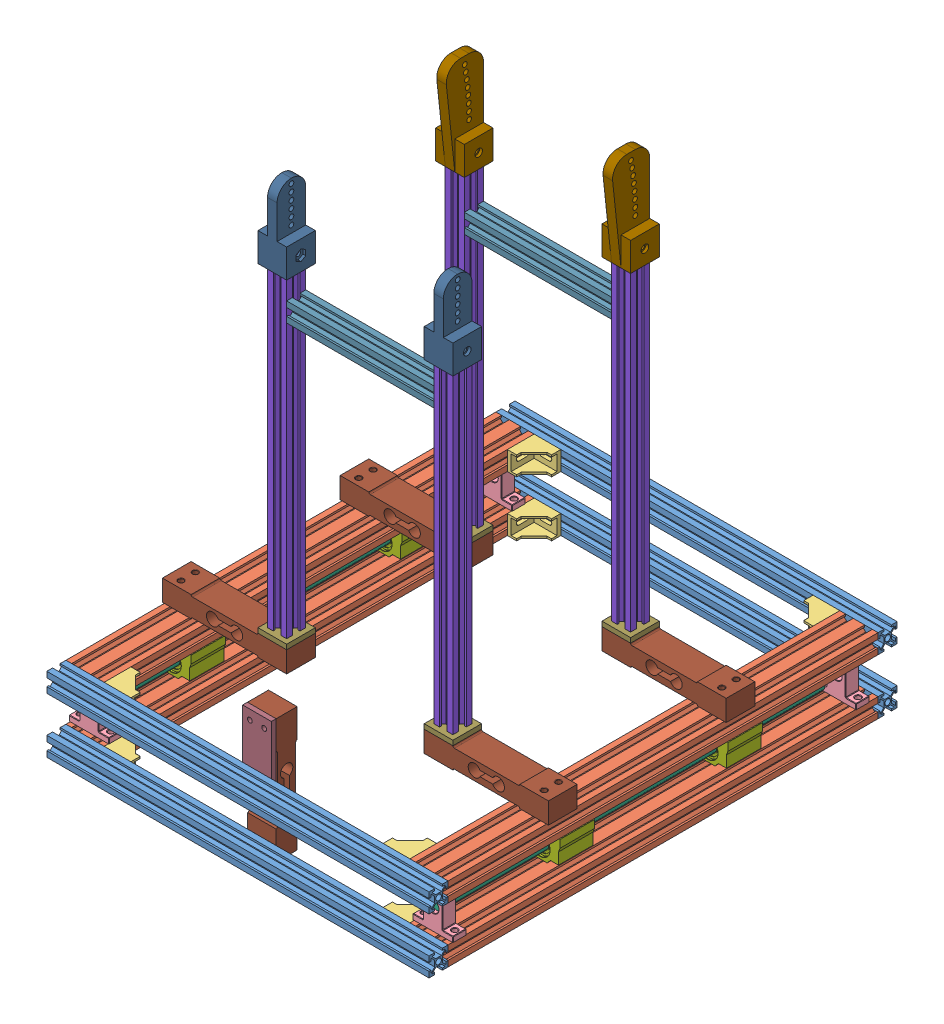
SolidWorks assembly Balança_Alt1, configuration Default. Lengths in mm.
Overall size (404 535 490).
56 component instances, 14 part files, 52 mates.
Components (placement in the parent):
- Quadrado2040-1: Quadrado2040 [Default] at (-124.633 620.1559 -302.6488) x (1 0 0) z (0 -1 0) size (400 490 20)
  - 20x20x400_profile-4: 20x20x400_profile [Default] at (-5.8923 594.8177 297.0396) x (0 1 0) z (0 0 1) size (20 400 20)
  - 20x20x400_profile-5: 20x20x400_profile [Default] at (-405.8923 124.8177 297.0396) x (0 -1 0) z (0 0 1) size (20 400 20)
  - 20x40x450_profile-3: 20x40x450_profile [Default] at (-395.8923 134.8177 297.0396) size (40 450 20)
  - 20x40x450_profile-4: 20x40x450_profile [Default] at (-35.8923 134.8177 297.0396) size (40 450 20)
  - cantoneira_20x20-1: cantoneira_20x20 [Default] at (-45.8923 134.8177 307.0396) x (0 0 -1) z (1 0 0) size (20 28 28)
  - cantoneira_20x20-2: cantoneira_20x20 [Default] at (-45.8923 584.8177 307.0396) x (0 0 -1) z (0 1 0) size (20 28 28)
  - cantoneira_20x20-3: cantoneira_20x20 [Default] at (-365.8923 584.8177 307.0396) x (0 0 -1) z (-1 0 0) size (20 28 28)
  - cantoneira_20x20-4: cantoneira_20x20 [Default] at (-365.8923 134.8177 307.0396) x (0 0 -1) z (0 -1 0) size (20 28 28)
- Quadrado2040-2: Quadrado2040 [Default] at (-124.633 678.1559 -302.6488) x (1 0 0) z (0 -1 0) size (400 490 20)
  - 20x20x400_profile-4: 20x20x400_profile [Default] at (-5.8923 594.8177 297.0396) x (0 1 0) z (0 0 1) size (20 400 20)
  - 20x20x400_profile-5: 20x20x400_profile [Default] at (-405.8923 124.8177 297.0396) x (0 -1 0) z (0 0 1) size (20 400 20)
  - 20x40x450_profile-3: 20x40x450_profile [Default] at (-395.8923 134.8177 297.0396) size (40 450 20)
  - 20x40x450_profile-4: 20x40x450_profile [Default] at (-35.8923 134.8177 297.0396) size (40 450 20)
  - cantoneira_20x20-1: cantoneira_20x20 [Default] at (-45.8923 134.8177 307.0396) x (0 0 -1) z (1 0 0) size (20 28 28)
  - cantoneira_20x20-2: cantoneira_20x20 [Default] at (-45.8923 584.8177 307.0396) x (0 0 -1) z (0 1 0) size (20 28 28)
  - cantoneira_20x20-3: cantoneira_20x20 [Default] at (-365.8923 584.8177 307.0396) x (0 0 -1) z (-1 0 0) size (20 28 28)
  - cantoneira_20x20-4: cantoneira_20x20 [Default] at (-365.8923 134.8177 307.0396) x (0 0 -1) z (0 -1 0) size (20 28 28)
- SK12-5: SK12 [Valor predeterminado] at (-504.83 350.1 -192.831) size (42 37.6 14)
  - Shaft support SK12-1: Shaft support SK12 [Valor predeterminado] at (-5.6953 6.0163 42) size (42 37.5 14)
  - m4x16-2: m4x16 [Valor predeterminado] at (4.3047 16.0441 42) x (-1 0 0) z (0 0.924225 0.381849) size (20 7 7)
- SK12-9: SK12 [Valor predeterminado] at (-504.83 350.1 229.169) size (42 37.6 14)
  - Shaft support SK12-1: Shaft support SK12 [Valor predeterminado] at (-5.6953 6.0163 42) size (42 37.5 14)
  - m4x16-2: m4x16 [Valor predeterminado] at (4.3047 16.0441 42) x (-1 0 0) z (0 0.924225 0.381849) size (20 7 7)
- SK12-10: SK12 [Valor predeterminado] at (-156.2206 350.1 -108.831) x (-1 0 0) z (0 0 -1) size (42 37.6 14)
  - Shaft support SK12-1: Shaft support SK12 [Valor predeterminado] at (-5.6953 6.0163 42) size (42 37.5 14)
  - m4x16-2: m4x16 [Valor predeterminado] at (4.3047 16.0441 42) x (-1 0 0) z (0 0.924225 0.381849) size (20 7 7)
- SK12-11: SK12 [Valor predeterminado] at (-156.2206 350.1 313.169) x (-1 0 0) z (0 0 -1) size (42 37.6 14)
  - Shaft support SK12-1: Shaft support SK12 [Valor predeterminado] at (-5.6953 6.0163 42) size (42 37.5 14)
  - m4x16-2: m4x16 [Valor predeterminado] at (4.3047 16.0441 42) x (-1 0 0) z (0 0.924225 0.381849) size (20 7 7)
- EixoLinear12mm-1: EixoLinear12mm [Default] at (-510.5253 356.1163 71.6299) x (0.524668 0.851307 0) z (0 0 1) size (12 12 400)
- EixoLinear12mm-2: EixoLinear12mm [Default] at (-150.5253 356.1163 73.8717) x (0.495907 0.868376 0) z (0 0 1) size (12 12 400)
- SC12UU-1: SC12UU [Default] at (-510.5253 371.1163 174.0893) size (42 28 36)
- SC12UU-2: SC12UU [Default] at (-150.5253 371.1163 148.1045) size (42 28 36)
- SC12UU-3: SC12UU [Default] at (-150.5253 371.1163 -27.6251) size (42 28 36)
- SC12UU-4: SC12UU [Default] at (-510.5253 371.1163 -46.4835) size (42 28 36)
- 20x20x500_profile-1: 20x20x500_profile [Default] at (-417.5253 418.1163 -21.8165) x (0 0 -1) z (1 0 0) size (20 350 20)
- 20x20x500_profile-2: 20x20x500_profile [Default] at (-243.5253 418.1163 -21.8165) x (0 0 -1) z (1 0 0) size (20 350 20)
- EncaixeAsaDianteiro-1: EncaixeAsaDianteiro [Default] at (-417.5253 748.1163 -21.8165) x (-1 0 0) z (0 0 -1) size (30 100 38.89)
- EncaixeAsaTraseiro-1: EncaixeAsaTraseiro [Default] at (-417.5253 748.1163 164.1658) size (30 80 30)
- EncaixeAsaDianteiro-4: EncaixeAsaDianteiro [Default] at (-243.5253 748.1163 -21.8165) x (-1 0 0) z (0 0 -1) size (30 100 38.89)
- load_cell_big_20kg-1: load_cell_big_20kg [Default] at (-345.5253 378.1163 266.169) x (1 0 0) z (0 -1 0) size (30 22 130)
- load_cell_big_20kg-2: load_cell_big_20kg [Default] at (-467.5253 402.1163 -6.8165) x (0 0 -1) z (1 0 0) size (30 22 130)
- Placa_de_conexao_celula_de_carga-1: Placa_de_conexao_celula_de_carga [Default] at (-417.5253 413.1163 -21.8165) x (0 0 -1) z (1 0 0) size (30 5 30)
- load_cell_big_20kg-4: load_cell_big_20kg [Default] at (-193.5253 402.1163 -6.8165) x (0 0 -1) z (1 0 0) size (30 22 130)
- Placa_de_conexao_celula_de_carga-2: Placa_de_conexao_celula_de_carga [Default] at (-243.5253 413.1163 -21.8165) x (0 0 -1) z (1 0 0) size (30 5 30)
- load_cell_big_20kg-7: load_cell_big_20kg [Default] at (-467.5253 402.1163 149.1658) x (0 0 1) z (-1 0 0) size (30 22 130)
- Placa_de_conexao_celula_de_carga-5: Placa_de_conexao_celula_de_carga [Default] at (-417.5253 413.1163 164.1658) x (0 0 1) z (-1 0 0) size (30 5 30)
- 20x20x500_profile-5: 20x20x500_profile [Default] at (-417.5253 418.1163 164.1658) x (0 0 1) z (-1 0 0) size (20 350 20)
- load_cell_big_20kg-8: load_cell_big_20kg [Default] at (-193.5253 402.1163 149.1658) x (0 0 1) z (-1 0 0) size (30 22 130)
- Placa_de_conexao_celula_de_carga-6: Placa_de_conexao_celula_de_carga [Default] at (-243.5253 413.1163 164.1658) x (0 0 1) z (-1 0 0) size (30 5 30)
- 20x20x500_profile-6: 20x20x500_profile [Default] at (-243.5253 418.1163 164.1658) x (0 0 1) z (-1 0 0) size (20 350 20)
- EncaixeAsaTraseiro-5: EncaixeAsaTraseiro [Default] at (-243.5253 748.1163 164.1658) x (-1 0 0) z (0 0 -1) size (30 80 30)
- Placa_de_conexao_celula_de_carga_2-1: Placa_de_conexao_celula_de_carga_2 [Default] at (-330.5253 407.1163 277.169) x (0 1 0) z (1 0 0) size (72 5 30)
- 20x20x154_profile-1: 20x20x154_profile [Default] at (-253.5253 701.6947 -21.8165) x (0 1 0) z (0 0 1) size (20 154 20)
- 20x20x154_profile-2: 20x20x154_profile [Default] at (-253.5253 714.3058 164.1658) x (0 1 0) z (0 0 1) size (20 154 20)
Mates (geometry in assembly coordinates):
- Coincident5: coincident anti-aligned: plane of Quadrado2040-1/20x40x450_profile-3 through (-516.5253 333.1163 282.169) normal (0 1 0); plane of SK12-5/Shaft support SK12-1 through (-510.5253 333.1163 -157.831) normal (0 -1 0)
- Distance1: distance = 1 mm aligned: plane of SK12-5/Shaft support SK12-1 through (-531.5253 307.9299 -157.831) normal (-1 0 0); plane of Quadrado2040-1/20x40x450_profile-3 through (-530.5253 319.1163 282.169) normal (-1 0 0)
- Distance2: distance = 10 mm aligned: plane of SK12-5/Shaft support SK12-1 through (-510.5253 307.9299 -157.831) normal (0 0 -1); plane of Quadrado2040-1/20x40x450_profile-3 through (-520.5253 323.1163 -167.831) normal (0 0 -1)
- Concentric1: concentric anti-aligned: cylinder of SK12-9/Shaft support SK12-1 through (-510.5253 356.1163 264.169) axis (0 0 1) radius 6; cylinder of EixoLinear12mm-1 through (-510.5253 356.1163 271.6299) axis (0 0 -1) radius 6
- Concentric2: concentric aligned: cylinder of SK12-10/Shaft support SK12-1 through (-150.5253 356.1163 -143.831) axis (0 0 -1) radius 6; cylinder of EixoLinear12mm-2 through (-150.5253 356.1163 273.8717) axis (0 0 -1) radius 6
- Concentric3: concentric anti-aligned: cylinder of EixoLinear12mm-1 through (-510.5253 356.1163 271.6299) axis (0 0 -1) radius 6; cylinder of SC12UU-1 through (-510.5253 356.1163 204.3646) axis (0 0 1) radius 6
- Concentric4: concentric anti-aligned: cylinder of EixoLinear12mm-1 through (-510.5253 356.1163 271.6299) axis (0 0 -1) radius 6; cylinder of SC12UU-4 through (-510.5253 356.1163 -16.2082) axis (0 0 1) radius 6
- Coincident9: coincident anti-aligned: cylinder of EixoLinear12mm-2 through (-150.5253 356.1163 273.8717) axis (0 0 -1) radius 6; circle of SC12UU-3
- Coincident10: coincident anti-aligned: cylinder of EixoLinear12mm-2 through (-150.5253 356.1163 273.8717) axis (0 0 -1) radius 6; circle of SC12UU-2
- Coincident11: coincident anti-aligned: plane of SC12UU-1 through (-499.5253 371.1163 192.0893) normal (0 1 0); plane of Quadrado2040-2/20x40x450_profile-3 through (-490.5253 371.1163 282.169) normal (0 -1 0)
- Coincident12: coincident anti-aligned: plane of SC12UU-4 through (-521.5253 371.1163 -28.4835) normal (0 1 0); plane of Quadrado2040-2/20x40x450_profile-3 through (-490.5253 371.1163 282.169) normal (0 -1 0)
- Coincident13: coincident anti-aligned: plane of SC12UU-2 through (-139.5253 371.1163 166.1045) normal (0 1 0); plane of Quadrado2040-2/20x40x450_profile-4 through (-156.5253 371.1163 282.169) normal (0 -1 0)
- Coincident14: coincident anti-aligned: plane of SC12UU-3 through (-161.5253 371.1163 -9.6251) normal (0 1 0); plane of Quadrado2040-2/20x40x450_profile-4 through (-156.5253 371.1163 282.169) normal (0 -1 0)
- Coincident15: coincident aligned: plane of Quadrado2040-1/20x20x400_profile-4 through (-530.5253 319.1163 302.169) normal (0 0 1); plane of Quadrado2040-2/20x20x400_profile-4 through (-530.5253 377.1163 302.169) normal (0 0 1)
- Coincident16: coincident aligned: plane of Quadrado2040-1/20x40x450_profile-3 through (-530.5253 333.1163 282.169) normal (-1 0 0); plane of Quadrado2040-2/20x40x450_profile-3 through (-530.5253 391.1163 282.169) normal (-1 0 0)
- Coincident25: coincident anti-aligned: plane of 20x20x500_profile-1 through (-417.5253 768.1163 -21.8165) normal (0 1 0); plane of EncaixeAsaDianteiro-1 through (-417.5253 768.1163 -21.8165) normal (0 -1 0)
- Coincident38: coincident anti-aligned: plane of 20x20x500_profile-2 through (-243.5253 768.1163 -21.8165) normal (0 1 0); plane of EncaixeAsaDianteiro-4 through (-243.5253 768.1163 -21.8165) normal (0 -1 0)
- Width1: width anti-aligned: plane of load_cell_big_20kg-2 through (-467.5253 402.1163 -6.8165) normal (0 0 1); plane of load_cell_big_20kg-2 through (-467.5253 402.1163 -36.8165) normal (0 0 -1); plane of 20x20x500_profile-1 through (-413.5253 768.1163 -31.8165) normal (0 0 -1); plane of 20x20x500_profile-1 through (-413.5253 768.1163 -11.8165) normal (0 0 1)
- Coincident85: coincident anti-aligned: plane of load_cell_big_20kg-2 through (-467.5253 413.1163 -36.8165) normal (0 1 0); plane of Placa_de_conexao_celula_de_carga-1 through (-417.5253 413.1163 -21.8165) normal (0 -1 0)
- Coincident86: coincident aligned: plane of load_cell_big_20kg-2 through (-402.5253 402.1163 -36.8165) normal (1 0 0); plane of Placa_de_conexao_celula_de_carga-1 through (-402.5253 418.1163 -6.8165) normal (1 0 0)
- Coincident87: coincident aligned: plane of load_cell_big_20kg-2 through (-467.5253 402.1163 -6.8165) normal (0 0 1); plane of Placa_de_conexao_celula_de_carga-1 through (-432.5253 418.1163 -6.8165) normal (0 0 1)
- Parallel2: parallel aligned: plane of 20x20x500_profile-1 through (-427.5253 768.1163 -11.8165) normal (0 0 1); plane of Placa_de_conexao_celula_de_carga-1 through (-432.5253 418.1163 -6.8165) normal (0 0 1)
- Width2: width anti-aligned: plane of Placa_de_conexao_celula_de_carga-1 through (-432.5253 418.1163 -6.8165) normal (0 0 1); plane of Placa_de_conexao_celula_de_carga-1 through (-432.5253 418.1163 -36.8165) normal (0 0 -1); plane of 20x20x500_profile-1 through (-427.5253 768.1163 -31.8165) normal (0 0 -1); plane of 20x20x500_profile-1 through (-427.5253 768.1163 -11.8165) normal (0 0 1)
- Width3: width anti-aligned: plane of Placa_de_conexao_celula_de_carga-1 through (-432.5253 418.1163 -6.8165) normal (-1 0 0); plane of Placa_de_conexao_celula_de_carga-1 through (-402.5253 418.1163 -6.8165) normal (1 0 0); plane of 20x20x500_profile-1 through (-407.5253 768.1163 -11.8165) normal (1 0 0); plane of 20x20x500_profile-1 through (-427.5253 768.1163 -11.8165) normal (-1 0 0)
- Coincident90: coincident anti-aligned: plane of 20x20x500_profile-1 through (-417.5253 418.1163 -21.8165) normal (0 -1 0); plane of Placa_de_conexao_celula_de_carga-1 through (-417.5253 418.1163 -21.8165) normal (0 1 0)
- Distance6: distance = 2 mm aligned: plane of load_cell_big_20kg-7 through (-532.5253 402.1163 179.1658) normal (-1 0 0); plane of Quadrado2040-2/20x40x450_profile-3 through (-530.5253 391.1163 282.169) normal (-1 0 0)
- Coincident101: coincident anti-aligned: plane of Quadrado2040-2/20x40x450_profile-3 through (-516.5253 391.1163 282.169) normal (0 1 0); plane of load_cell_big_20kg-7 through (-467.5253 391.1163 179.1658) normal (0 -1 0)
- Coincident103: coincident aligned: plane of load_cell_big_20kg-7 through (-467.5253 402.1163 149.1658) normal (0 0 -1); plane of Placa_de_conexao_celula_de_carga-5 through (-402.5253 418.1163 149.1658) normal (0 0 -1)
- Coincident104: coincident aligned: plane of load_cell_big_20kg-7 through (-402.5253 402.1163 179.1658) normal (1 0 0); plane of Placa_de_conexao_celula_de_carga-5 through (-402.5253 418.1163 149.1658) normal (1 0 0)
- Coincident105: coincident anti-aligned: plane of load_cell_big_20kg-7 through (-467.5253 413.1163 179.1658) normal (0 1 0); plane of Placa_de_conexao_celula_de_carga-5 through (-417.5253 413.1163 164.1658) normal (0 -1 0)
- Coincident106: coincident anti-aligned: plane of Placa_de_conexao_celula_de_carga-5 through (-417.5253 418.1163 164.1658) normal (0 1 0); plane of 20x20x500_profile-5 through (-417.5253 418.1163 164.1658) normal (0 -1 0)
- Width4: width anti-aligned: plane of Placa_de_conexao_celula_de_carga-5 through (-402.5253 418.1163 179.1658) normal (0 0 1); plane of Placa_de_conexao_celula_de_carga-5 through (-402.5253 418.1163 149.1658) normal (0 0 -1); plane of 20x20x500_profile-5 through (-421.5253 768.1163 154.1658) normal (0 0 -1); plane of 20x20x500_profile-5 through (-421.5253 768.1163 174.1658) normal (0 0 1)
- Width5: width anti-aligned: plane of 20x20x500_profile-5 through (-427.5253 768.1163 154.1658) normal (-1 0 0); plane of 20x20x500_profile-5 through (-407.5253 768.1163 154.1658) normal (1 0 0); plane of Placa_de_conexao_celula_de_carga-5 through (-402.5253 418.1163 149.1658) normal (1 0 0); plane of Placa_de_conexao_celula_de_carga-5 through (-432.5253 418.1163 149.1658) normal (-1 0 0)
- Coincident107: coincident anti-aligned: plane of EncaixeAsaTraseiro-1 through (-417.5253 768.1163 164.1658) normal (0 -1 0); plane of 20x20x500_profile-5 through (-417.5253 768.1163 164.1658) normal (0 1 0)
- Width6: width anti-aligned: plane of load_cell_big_20kg-1 through (-345.5253 378.1163 266.169) normal (-1 0 0); plane of load_cell_big_20kg-1 through (-315.5253 378.1163 266.169) normal (1 0 0); plane of Quadrado2040-2/20x20x400_profile-4 through (-130.5253 381.1163 292.169) normal (1 0 0); plane of Quadrado2040-2/20x20x400_profile-4 through (-530.5253 381.1163 292.169) normal (-1 0 0)
- Coincident113: coincident aligned: plane of Quadrado2040-1/20x20x400_profile-4 through (-530.5253 313.1163 282.169) normal (0 -1 0); plane of load_cell_big_20kg-1 through (-315.5253 313.1163 266.169) normal (0 -1 0)
- Coincident114: coincident aligned: plane of load_cell_big_20kg-1 through (-315.5253 443.1163 266.169) normal (0 1 0); plane of Placa_de_conexao_celula_de_carga_2-1 through (-345.5253 443.1163 282.169) normal (0 1 0)
- Coincident115: coincident aligned: plane of load_cell_big_20kg-1 through (-345.5253 378.1163 266.169) normal (-1 0 0); plane of Placa_de_conexao_celula_de_carga_2-1 through (-345.5253 371.1163 282.169) normal (-1 0 0)
- Coincident116: coincident anti-aligned: plane of load_cell_big_20kg-1 through (-315.5253 378.1163 277.169) normal (0 0 1); plane of Placa_de_conexao_celula_de_carga_2-1 through (-330.5253 407.1163 277.169) normal (0 0 -1)
- Coincident117: coincident anti-aligned: plane of Quadrado2040-2/20x20x400_profile-4 through (-530.5253 391.1163 282.169) normal (0 0 -1); plane of Placa_de_conexao_celula_de_carga_2-1 through (-330.5253 407.1163 282.169) normal (0 0 1)
- Distance7: distance = 2 mm aligned: plane of Quadrado2040-2/20x40x450_profile-3 through (-530.5253 391.1163 282.169) normal (-1 0 0); plane of load_cell_big_20kg-2 through (-532.5253 402.1163 -36.8165) normal (-1 0 0)
- Coincident122: coincident anti-aligned: plane of Quadrado2040-2/20x40x450_profile-3 through (-516.5253 391.1163 282.169) normal (0 1 0); plane of load_cell_big_20kg-2 through (-467.5253 391.1163 -36.8165) normal (0 -1 0)
- Coincident123: coincident anti-aligned: plane of EncaixeAsaTraseiro-1 through (-427.5253 768.1163 174.1658) normal (0 0 -1); plane of 20x20x500_profile-5 through (-407.5253 768.1163 174.1658) normal (0 0 1)
- Coincident124: coincident anti-aligned: plane of EncaixeAsaTraseiro-1 through (-407.5253 768.1163 154.1658) normal (-1 0 0); plane of 20x20x500_profile-5 through (-407.5253 768.1163 168.1658) normal (1 0 0)
- Coincident125: coincident anti-aligned: plane of 20x20x500_profile-1 through (-413.5253 768.1163 -11.8165) normal (0 0 1); plane of EncaixeAsaDianteiro-1 through (-407.5253 768.1163 -11.8165) normal (0 0 -1)
- Coincident126: coincident anti-aligned: plane of 20x20x500_profile-1 through (-407.5253 768.1163 -11.8165) normal (1 0 0); plane of EncaixeAsaDianteiro-1 through (-407.5253 768.1163 -11.8165) normal (-1 0 0)
- Coincident127: coincident anti-aligned: plane of 20x20x500_profile-2 through (-253.5253 768.1163 -11.8165) normal (0 0 1); plane of EncaixeAsaDianteiro-4 through (-233.5253 768.1163 -11.8165) normal (0 0 -1)
- Coincident128: coincident anti-aligned: plane of 20x20x500_profile-2 through (-253.5253 768.1163 -11.8165) normal (-1 0 0); plane of EncaixeAsaDianteiro-4 through (-253.5253 768.1163 -11.8165) normal (1 0 0)
- Coincident129: coincident anti-aligned: plane of 20x20x500_profile-1 through (-407.5253 768.1163 -11.8165) normal (1 0 0); plane of 20x20x154_profile-1 through (-407.5253 701.6947 -21.8165) normal (-1 0 0)
- Coincident130: coincident aligned: plane of 20x20x500_profile-1 through (-413.5253 768.1163 -31.8165) normal (0 0 -1); plane of 20x20x154_profile-1 through (-407.5253 705.6947 -31.8165) normal (0 0 -1)
- Coincident131: coincident anti-aligned: plane of 20x20x500_profile-6 through (-253.5253 768.1163 168.1658) normal (-1 0 0); plane of 20x20x154_profile-2 through (-253.5253 714.3058 164.1658) normal (1 0 0)
- Coincident132: coincident aligned: plane of 20x20x500_profile-6 through (-233.5253 768.1163 174.1658) normal (0 0 1); plane of 20x20x154_profile-2 through (-407.5253 704.3058 174.1658) normal (0 0 1)
